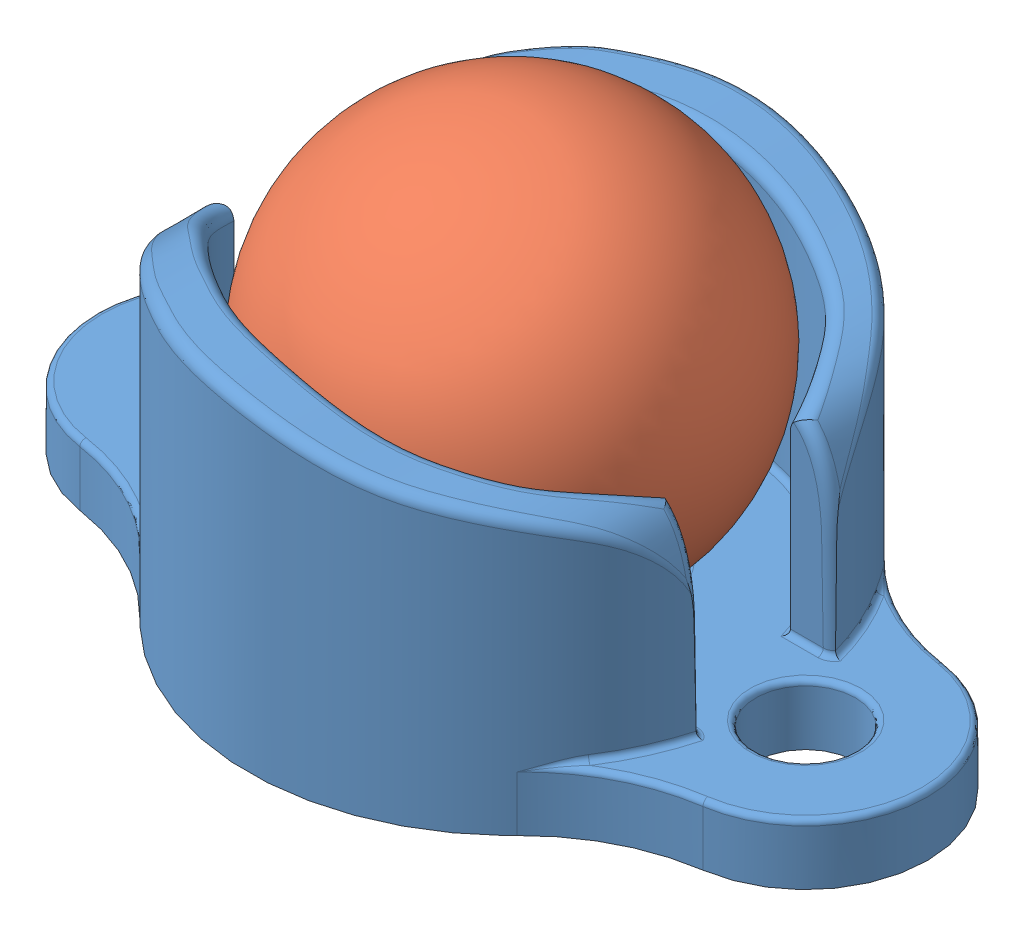
SolidWorks assembly Pololu Ball Caster, configuration Predeterminado. Lengths in mm.
Overall size (19.05 10.36 12.25).
2 component instances, 2 part files, 2 mates.
Components (placement in the parent):
- base-1: base [Predeterminado] at origin size (19.05 7.74 12.25)
- ball-1: ball [Predeterminado] at (0 4.8155 0) x (0.999099 0.024067 0.034961) z (-0.035416 0.018735 0.999197) size (9.3 9.3 9.3)
Mates (geometry in assembly coordinates):
- Concéntrica1: concentric: cylinder of base-1 through (0 0.6945 0) axis (0 -1 0) radius 2.856; sphere of ball-1
- Tangente2: tangent: sphere of ball-1; line of assembly
